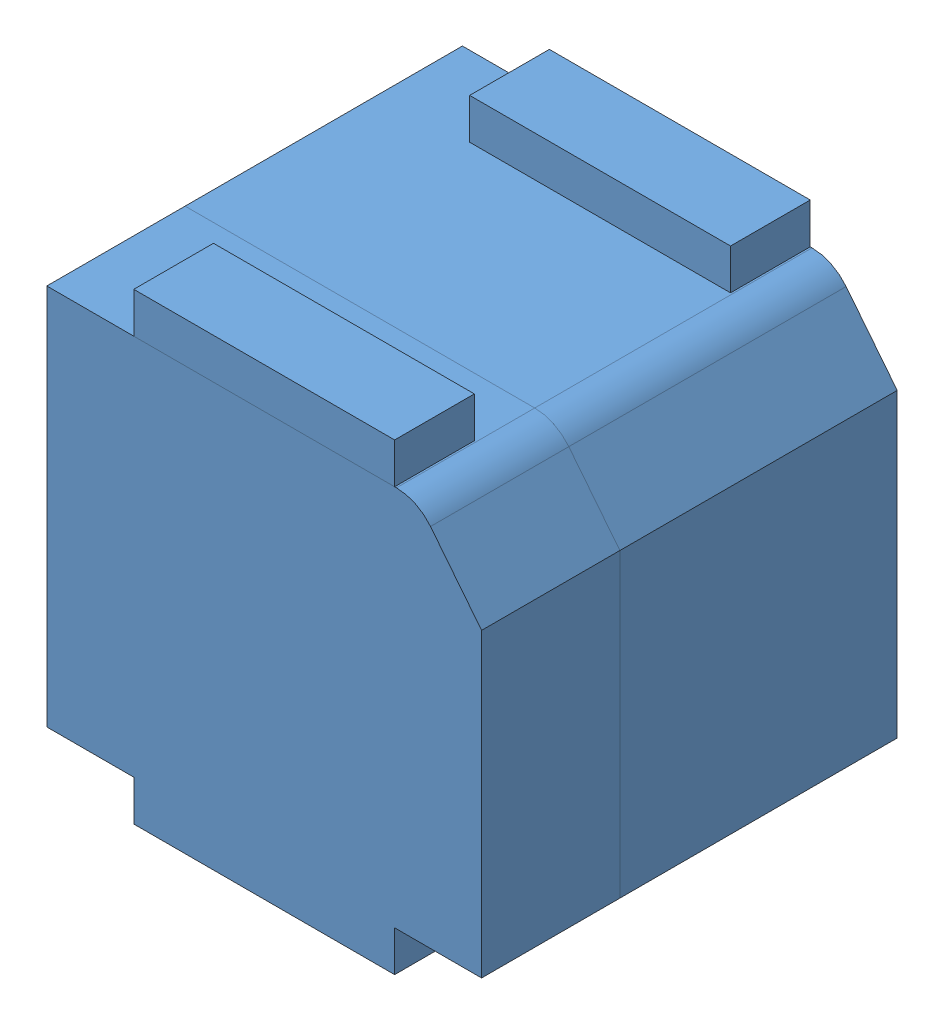
SolidWorks assembly mold assembly R2, configuration Default. Lengths in mm.
Overall size (300 319.52 286.77).
4 component instances, 4 part files, 4 mates.
Components (placement in the parent):
- MOLD R3.0 FULL BLOCK-1: MOLD R3.0 FULL BLOCK [Default] at (-88.4118 -197.8799 179.4534) size (300 319.52 286.77)
- CARBON WHEEL INSIDE SHELL (SOLID - FOR MOLD) R3.0-1: CARBON WHEEL INSIDE SHELL (SOLID - FOR MOLD) R3.0 [Default] at (61.5882 -66.1174 324.8536) x (0 1 0) z (1 0 0) size (276.85 155.45 276.85) (hidden)
- CARBON WHEEL OUTSIDE SHELL (SOLID - FOR MOLD) R3.0-1: CARBON WHEEL OUTSIDE SHELL (SOLID - FOR MOLD) R3.0 [Default] at (61.5882 -66.1174 349.8536) x (1 0 0) z (0 -1 0) size (277.11 100.32 277.11) (hidden)
- 1126352-Fastenal-02-02-2019.stp-1: 1126352-Fastenal-02-02-2019.stp [Default] at (-63.3976 -176.1203 536.9616) x (0 0 -1) z (1 0 0) (suppressed, hidden)
Mates (geometry in assembly coordinates):
- Distance1: distance = 3 mm: plane of ? through (-92.5951 -198.2873 438.2189) normal (0 0 1); plane of MOLD R3.0 FULL BLOCK-1 through (-88.4118 -197.8799 441.2189) normal (0 0 1)
- Distance2: distance = 25 mm: plane of CARBON WHEEL OUTSIDE SHELL (SOLID - FOR MOLD) R3.0-1 through (61.5882 -66.1174 362.9009) normal (0 0 -1); plane of CARBON WHEEL INSIDE SHELL (SOLID - FOR MOLD) R3.0-1 through (61.5882 -66.1174 337.9009) normal (0 0 1)
- Concentric2: concentric: circle of CARBON WHEEL INSIDE SHELL (SOLID - FOR MOLD) R3.0-1; circle of CARBON WHEEL OUTSIDE SHELL (SOLID - FOR MOLD) R3.0-1
- Coincident7: coincident: point of MOLD R3.0 FULL BLOCK-1; point of CARBON WHEEL OUTSIDE SHELL (SOLID - FOR MOLD) R3.0-1
